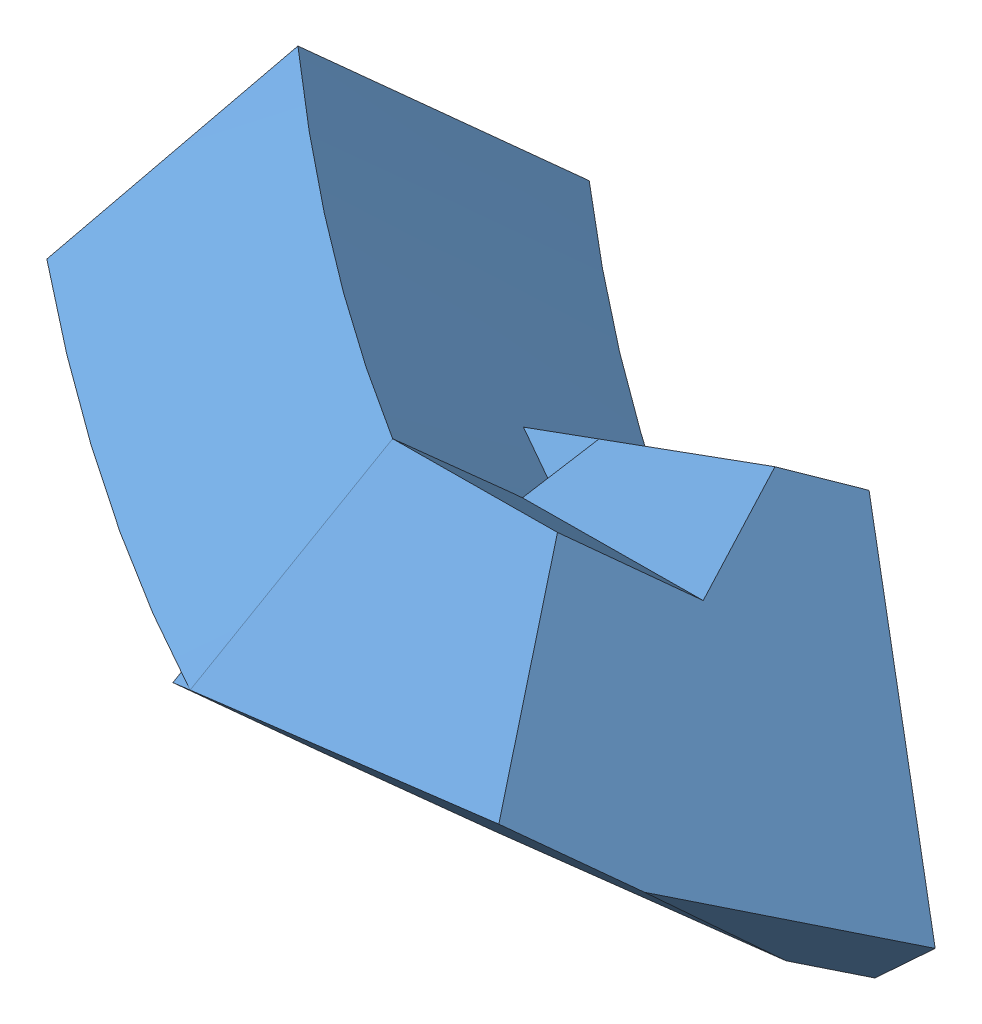
SolidWorks assembly Сборка1, configuration По умолчанию. Lengths in mm.
Overall size (270.91 239.79 235.47).
2 component instances, 2 part files, 3 mates.
Components (placement in the parent):
- helmet with face v3-1: helmet with face v3 [По умолчанию] at origin size (270.91 239.79 235.47)
- prisma-1: prisma [По умолчанию] at (-490.047 902.3923 4097.6856) x (0.17065 -0.807145 0.565151) z (-0.985169 -0.150184 0.082985) size (25 30 30) (hidden)
Mates (geometry in assembly coordinates):
- Совпадение1: coincident: line of helmet with face v3-1 through (-507.9012 899.9053 4061.9824) axis (0.156234 -0.58518 0.79571); point of prisma-1
- Перпендикулярность1: perpendicular: line of helmet with face v3-1 through (-507.9012 899.9053 4061.9824) axis (0.156234 -0.58518 0.79571); plane of prisma-1 through (-519.3337 889.3229 4087.8631) normal (-0.156234 0.58518 -0.79571)
- Совпадение3: coincident: point of helmet with face v3-1; point of prisma-1
